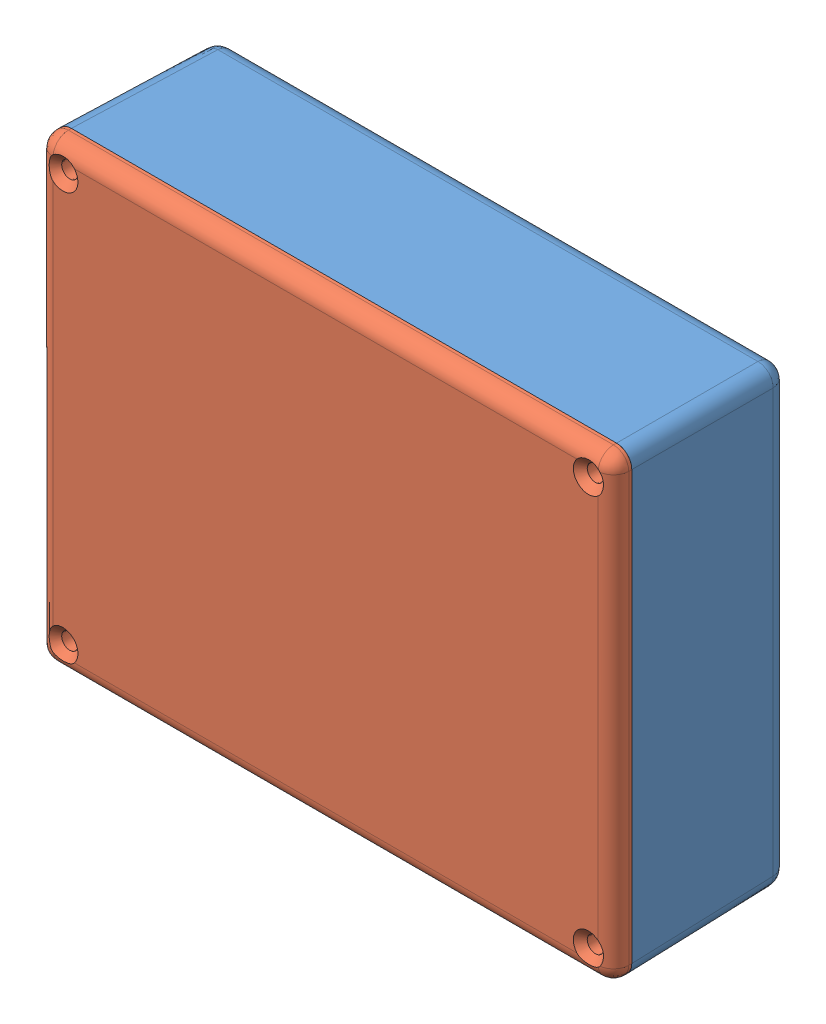
SolidWorks assembly Assem1, configuration Default. Lengths in mm.
Overall size (119.63 95.25 36.83).
2 component instances, 2 part files, 3 mates.
Components (placement in the parent):
- 11351_body-1: 11351_body [Default] at (12.3075 40.7873 123.6041) size (119.63 95.25 33.02)
- 11351_lid-1: 11351_lid [Default] at (131.9419 40.7871 127.4141) x (-1 -0.000001 0) z (0.000001 -1 0) size (119.63 5.84 95.25)
Mates (geometry in assembly coordinates):
- Coincident1: coincident: plane of 11351_body-1 through (12.3075 40.7873 123.6041) normal (0 0 1); plane of 11351_lid-1 through (121.5272 51.2016 123.6041) normal (0 0 -1)
- Concentric1: concentric: cylinder of 11351_lid-1 through (126.7342 45.9946 127.4141) axis (0 0 1) radius 1.7; cylinder of 11351_body-1 through (126.7342 45.9946 120.5561) axis (0 0 1) radius 1.65
- Concentric3: concentric aligned: cylinder of 11351_body-1 through (17.5148 130.83 120.5561) axis (0 0 1) radius 1.65; cylinder of 11351_lid-1 through (17.5148 130.83 127.4141) axis (0 0 1) radius 1.7
